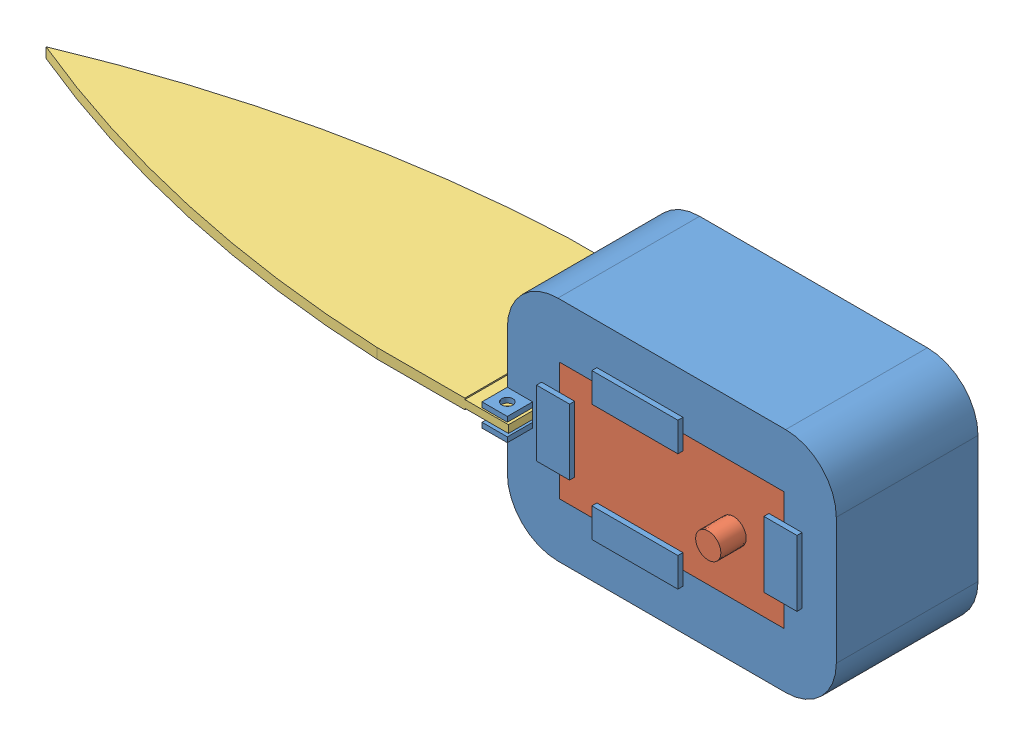
SolidWorks assembly 1fin_tail, configuration 預設. Lengths in mm.
Overall size (170.1 45 38).
3 component instances, 3 part files, 7 mates.
Components (placement in the parent):
- bus2_tail-1: bus2_tail [預設] at (20.7115 2.6893 51) size (65 45 38)
- bus_servo-1: bus_servo [預設] at (13.2247 -8.8039 51) x (1 0 0) z (0 -1 0) size (44.4 38 23.4)
- bus_final_tail_1-1: bus_final_tail_1 [預設] at (-43.3138 2.6893 64.2694) x (-1 0 0.00071) z (0 1 0) size (110.1 37.8 2)
Mates (geometry in assembly coordinates):
- 重合/共線/共點1: coincident: plane of bus2_tail-1 through (20.7115 2.6893 79) normal (0 0 1); plane of bus_servo-1 through (13.2247 -8.8039 79) normal (0 0 1)
- 重合/共線/共點2: coincident: plane of bus2_tail-1 through (20.7115 2.6893 51) normal (0 0 -1); plane of bus_servo-1 through (13.2247 -8.8039 51) normal (0 0 -1)
- 重合/共線/共點3: coincident: plane of bus2_tail-1 through (-28.9231 14.3893 90) normal (0 -1 0); plane of bus_servo-1 through (-28.9231 14.3893 79) normal (0 1 0)
- 重合/共線/共點4: coincident anti-aligned: plane of bus2_tail-1 through (-28.9231 14.3893 90) normal (1 0 0); plane of bus_servo-1 through (-28.9231 14.3893 79) normal (-1 0 0)
- 平行相距1: distance = 0.5 mm anti-aligned: plane of bus_final_tail_1-1 through (-43.3138 3.4393 64.2694) normal (0 1 0); plane of bus2_tail-1 through (20.7115 3.9393 51) normal (0 -1 0)
- 同軸心1: concentric anti-aligned: cylinder of bus2_tail-1 through (-36.7231 7.6893 48.5) axis (0 -1 0) radius 1.1; cylinder of bus_final_tail_1-1 through (-36.7231 1.4393 48.5) axis (0 1 0) radius 1.1
- 同軸心2: concentric anti-aligned: cylinder of bus2_tail-1 through (-36.7231 7.6893 81.5) axis (0 -1 0) radius 1.1; cylinder of bus_final_tail_1-1 through (-36.7231 1.4393 81.5) axis (0 1 0) radius 1.1
